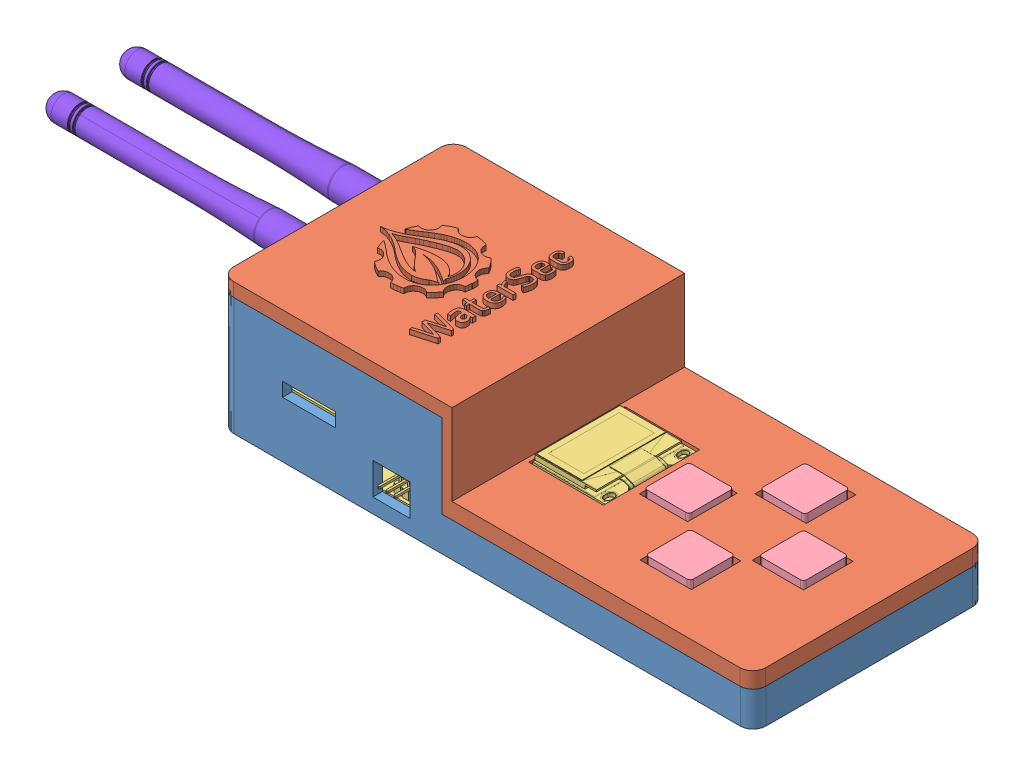
SolidWorks assembly Assemblage_carte_box, configuration Défaut. Lengths in mm.
Overall size (254.67 42.67 74.02).
19 component instances, 8 part files, 24 mates.
Components (placement in the parent):
- box-1: box [Défaut] at (-16.9941 -24.6803 152.5) x (1 0 0) z (0 -1 0) size (166 72.5 36.9)
- Pièce17-2: Pièce17 [Défaut] at (-30.9941 -8.3369 188.8472) x (0 0 -1) z (0 1 0) size (72.6 166 34.84)
- BOARD_SOLID-1: BOARD_SOLID [Défaut] at (37.5092 -16.1997 142.2063) x (1 0 0.000619) z (0 1 0) size (156.59 71.23 29.71)
- bouttom-1: bouttom [Défaut] at (13.9738 -10.4031 142.8016) x (1 0 0) z (0 -1 0) size (13.95 13.95 3)
- bouttom-2: bouttom [Défaut] at (32.2167 -13.4031 174.5929) x (1 0 0) z (0 1 0) size (13.95 13.95 3)
- bouttom-3: bouttom [Défaut] at (32.18 -13.4031 138.7892) x (1 0 0) z (0 1 0) size (13.95 13.95 3)
- bouttom-4: bouttom [Défaut] at (50.07 -13.4031 157.0848) x (1 0 0) z (0 1 0) size (13.95 13.95 3)
- Antena 3 dBi 5.8 GHz v3.step-1: Antena 3 dBi 5.8 GHz v3.step [Défaut] at (-66.5351 -1.5656 130.1344) x (0 0.244684 0.969603) z (-1 0 0) size (10.52 9.82 109.35)
  - Sma.step-1: Sma.step [Défaut] at (0.0007 0 34.7819) x (-1 0 0) z (0 0 -1) size (9.8 9.82 11)
  - Antena-1.step-1: Antena-1.step [Défaut] at (0.0007 0 22.0819) size (9.5 9.5 20.1)
  - Antena-2.step-1: Antena-2.step [Défaut] at (0.0007 -1.05 39.0819) x (1 0 0) z (0 -1 0) size (2.05 2.07 3.71)
  - Antena-2.step-2: Antena-2.step [Défaut] at (0.0007 1.05 39.0819) x (1 0 0) z (0 1 0) size (2.05 2.07 3.71)
  - Antena-stick.step-1: Antena-stick.step [Défaut] at (0.0007 0 34.0819) x (0 1 0) z (0 0 1) size (9.7 10.52 88.26)
- Antena 3 dBi 5.8 GHz v3.step-2: Antena 3 dBi 5.8 GHz v3.step [Défaut] at (-66.1596 -1.562 153.5011) x (0 -0.708928 0.705281) z (-1 0 0) size (10.52 9.82 109.35)
  - Sma.step-1: Sma.step [Défaut] at (0.0007 0 34.7819) x (-1 0 0) z (0 0 -1) size (9.8 9.82 11)
  - Antena-1.step-1: Antena-1.step [Défaut] at (0.0007 0 22.0819) size (9.5 9.5 20.1)
  - Antena-2.step-1: Antena-2.step [Défaut] at (0.0007 -1.05 39.0819) x (1 0 0) z (0 -1 0) size (2.05 2.07 3.71)
  - Antena-2.step-2: Antena-2.step [Défaut] at (0.0007 1.05 39.0819) x (1 0 0) z (0 1 0) size (2.05 2.07 3.71)
  - Antena-stick.step-1: Antena-stick.step [Défaut] at (0.0007 0 34.0819) x (0 1 0) z (0 0 1) size (9.7 10.52 88.26)
Mates (geometry in assembly coordinates):
- Coïncidente11: coincident anti-aligned: plane of box-1 through (-16.9941 -24.6803 185.75) normal (0 0 -1); plane of Pièce17-2 through (-33.9941 2.3197 185.75) normal (0 0 1)
- Coïncidente12: coincident anti-aligned: plane of box-1 through (-16.9941 9.2197 152.5) normal (0 1 0); plane of Pièce17-2 through (-30.9941 9.2197 103.8472) normal (0 -1 0)
- Coïncidente14: coincident anti-aligned: plane of box-1 through (-16.9941 -24.6803 152.5) normal (0 1 0); plane of BOARD_SOLID-1 through (-18.8651 -24.6803 152.3809) normal (0 -1 0)
- Verrouiller2: lock: unknown of box-1; unknown of BOARD_SOLID-1
- Distance1: distance = 0.816 mm anti-aligned: plane of Pièce17-2 through (14.3912 -21.8503 157.5676) normal (0 0 -1); plane of bouttom-1 through (13.9738 -13.4031 156.7516) normal (0 0 1)
- Distance2: distance = 0.6879 mm anti-aligned: plane of Pièce17-2 through (-0.6641 -21.8503 142.1152) normal (1 0 0); plane of bouttom-1 through (0.0238 -13.4031 142.8016) normal (-1 0 0)
- Coïncidente24: coincident anti-aligned: plane of box-1 through (-30.9941 5.3197 85.75) normal (1 0 0); plane of Pièce17-2 through (-30.9941 -12.3503 118.8472) normal (-1 0 0)
- Distance3: distance = 1.4472 mm aligned: plane of Pièce17-2 through (-27.8496 -11.8503 95.6472) normal (0 1 0); plane of bouttom-1 through (13.9738 -10.4031 142.8016) normal (0 1 0)
- Coïncidente26: coincident aligned: plane of bouttom-1 through (13.9738 -10.4031 142.8016) normal (0 1 0); plane of bouttom-2 through (32.2167 -10.4031 174.5929) normal (0 1 0)
- Parallèle4: parallel anti-aligned: plane of Pièce17-2 through (33.3043 -21.8503 175.3164) normal (-1 0 0); plane of bouttom-2 through (32.2167 -10.4031 174.5929) normal (1 0 0)
- Distance4: distance = 0.7235 mm anti-aligned: plane of Pièce17-2 through (17.3043 -21.8503 175.3164) normal (0 0 -1); plane of bouttom-2 through (32.2167 -10.4031 174.5929) normal (0 0 1)
- Distance5: distance = 1.0876 mm anti-aligned: plane of bouttom-2 through (32.2167 -10.4031 174.5929) normal (1 0 0); plane of Pièce17-2 through (33.3043 -21.8503 175.3164) normal (-1 0 0)
- Coïncidente30: coincident aligned: plane of bouttom-1 through (13.9738 -10.4031 142.8016) normal (0 1 0); plane of bouttom-3 through (32.18 -10.4031 138.7892) normal (0 1 0)
- Parallèle5: parallel anti-aligned: plane of Pièce17-2 through (33.357 -21.8503 139.5099) normal (-1 0 0); plane of bouttom-3 through (32.18 -10.4031 138.7892) normal (1 0 0)
- Distance7: distance = 1.1769 mm anti-aligned: plane of Pièce17-2 through (33.357 -21.8503 139.5099) normal (-1 0 0); plane of bouttom-3 through (32.18 -10.4031 138.7892) normal (1 0 0)
- Distance8: distance = 0.7207 mm anti-aligned: plane of Pièce17-2 through (17.357 -21.8503 139.5099) normal (0 0 -1); plane of bouttom-3 through (32.18 -10.4031 138.7892) normal (0 0 1)
- Coïncidente35: coincident aligned: plane of bouttom-2 through (32.2167 -10.4031 174.5929) normal (0 1 0); plane of bouttom-4 through (50.07 -10.4031 157.0848) normal (0 1 0)
- Parallèle6: parallel anti-aligned: plane of Pièce17-2 through (50.9052 -21.8503 157.9219) normal (-1 0 0); plane of bouttom-4 through (50.07 -10.4031 157.0848) normal (1 0 0)
- Distance9: distance = 1.2149 mm anti-aligned: plane of Pièce17-2 through (34.9052 -21.8503 157.9219) normal (1 0 0); plane of bouttom-4 through (36.12 -10.4031 157.0848) normal (-1 0 0)
- Distance10: distance = 0.8371 mm anti-aligned: plane of Pièce17-2 through (34.9052 -21.8503 157.9219) normal (0 0 -1); plane of bouttom-4 through (50.07 -10.4031 157.0848) normal (0 0 1)
- Coaxiale1: concentric anti-aligned: cylinder of box-1 through (-39.9941 -1.5654 130.1352) axis (-1 0 0) radius 3.75; circle of Antena 3 dBi 5.8 GHz v3.step-1/Sma.step-1
- Verrouiller3: lock: unknown of box-1; unknown of Antena 3 dBi 5.8 GHz v3.step-1/Antena-stick.step-1
- Coaxiale2: concentric anti-aligned: circle of box-1; circle of Antena 3 dBi 5.8 GHz v3.step-2/Sma.step-1
- Verrouiller4: lock: unknown of box-1; unknown of Antena 3 dBi 5.8 GHz v3.step-2/Antena-stick.step-1
